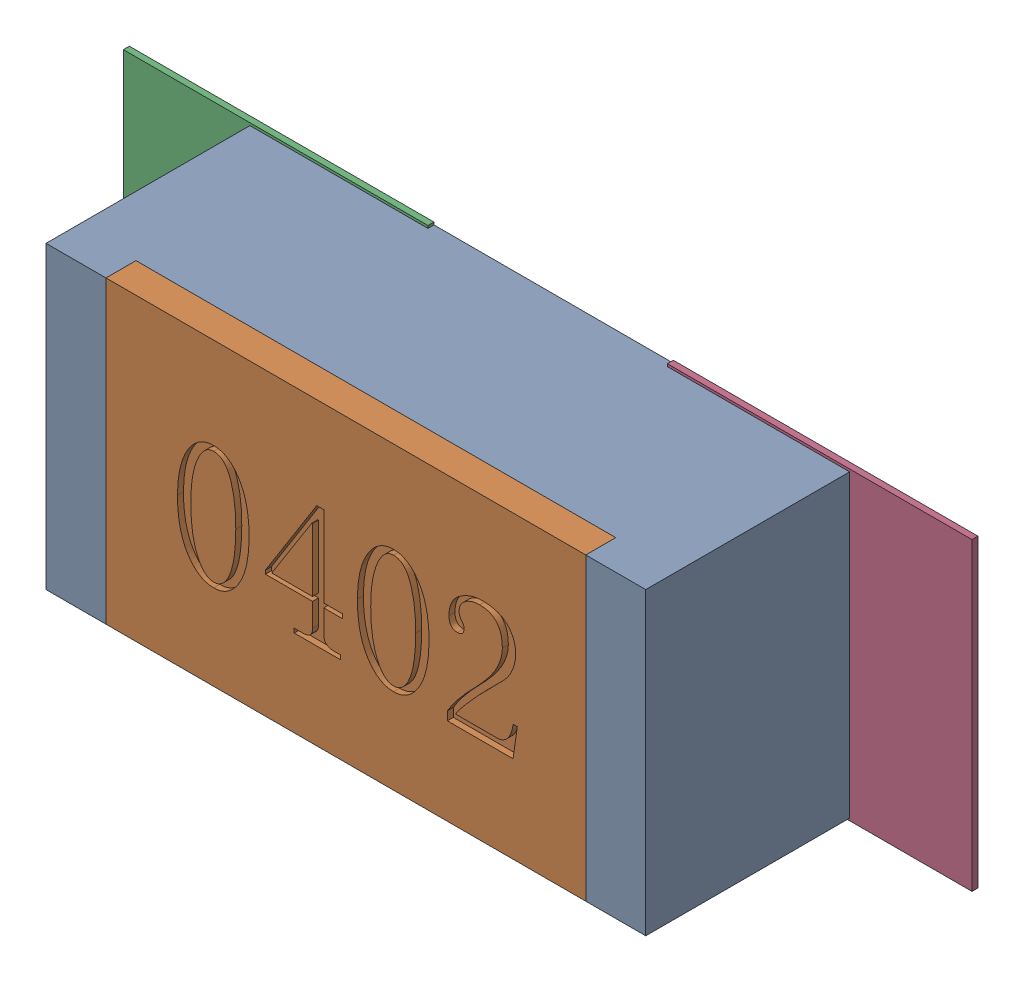
SolidWorks assembly R139, configuration Défaut. Lengths in mm.
Overall size (1.42 0.51 0.35).
5 component instances, 2 part files, 0 mates.
Components (placement in the parent):
- R0402-1: R0402 [Défaut] at (13.7414 -22.2505 0) x (1 0 0) z (0 0 1) size (1 0.5 0.35)
- 6504207776-1: 6504207776 [Défaut] at (13.2843 -22.2504 0) size (0.51 0.51 0.01)
  - Extruded-1: Extruded [Défaut] at origin size (0.51 0.51 0.01)
- 6504207776-2: 6504207776 [Défaut] at (14.1914 -22.2504 0) size (0.51 0.51 0.01)
  - Extruded-1: Extruded [Défaut] at origin size (0.51 0.51 0.01)
